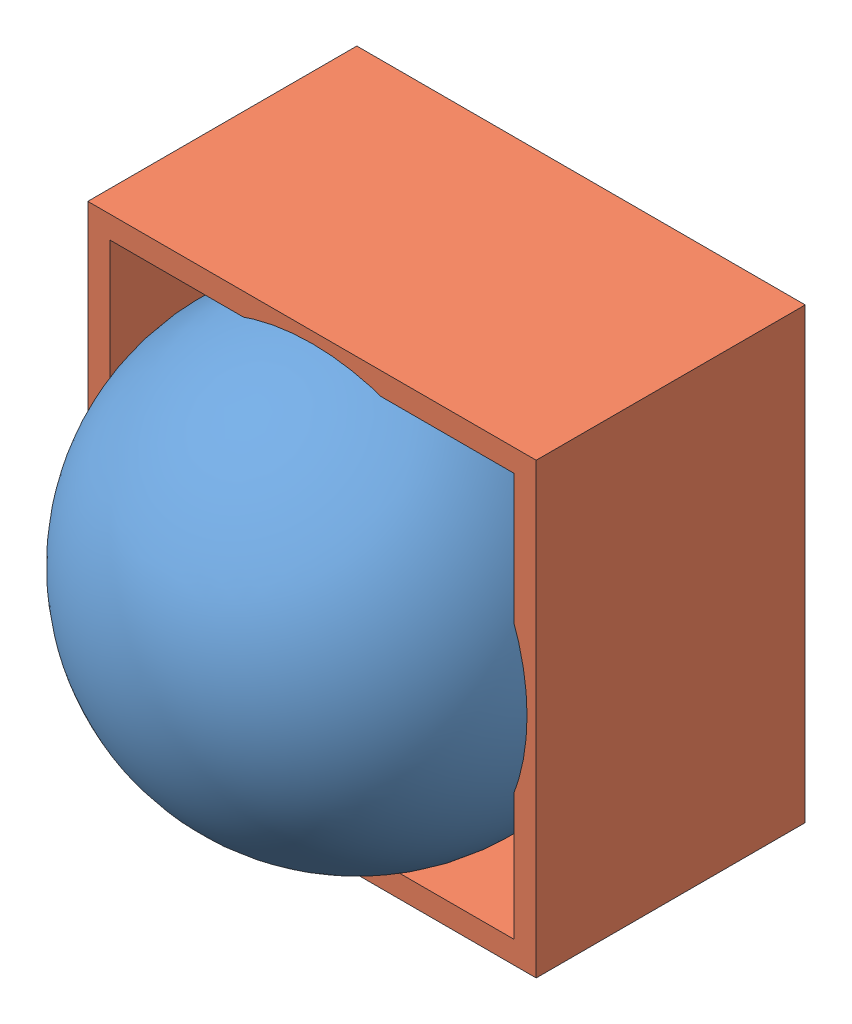
SolidWorks assembly BearingContainerAsm, configuration Default. Lengths in mm.
Overall size (50 50 49.48).
2 component instances, 2 part files, 0 mates.
Components (placement in the parent):
- miniball-2: miniball [Default] at (64.8074 28.9122 72.7375) size (49 49 49)
- container-3: container [Default] at (97.5898 25.7275 23.2563) x (-1 0 0) z (0 0 -1) size (50 50 30)
